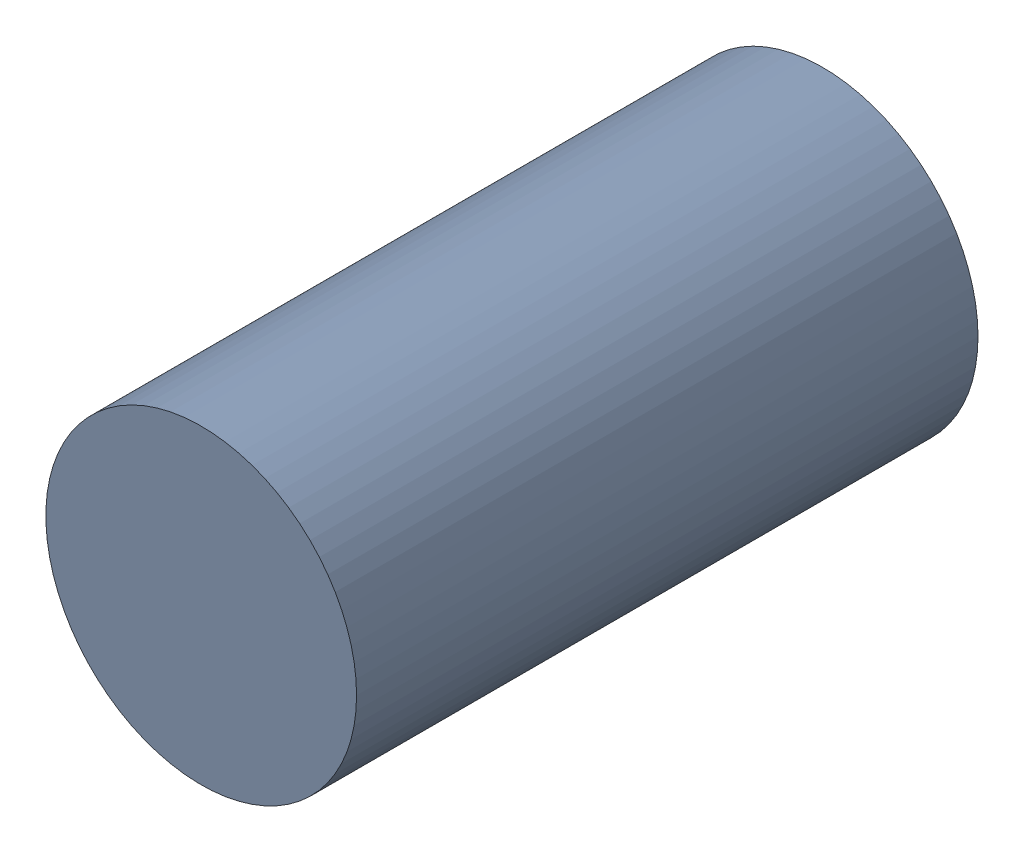
SolidWorks assembly MH6_1.step, configuration Default. Lengths in mm.
Overall size (1 1 2).
2 component instances, 1 part files, 0 mates.
Components (placement in the parent):
- 9228463120_1.step-3: 9228463120_1.step [Default] at (500.126 316.992 -1.5) size (1 1 2)
  - Cylinder_1.step-26: Cylinder_1.step [Default] at origin size (1 1 2)
